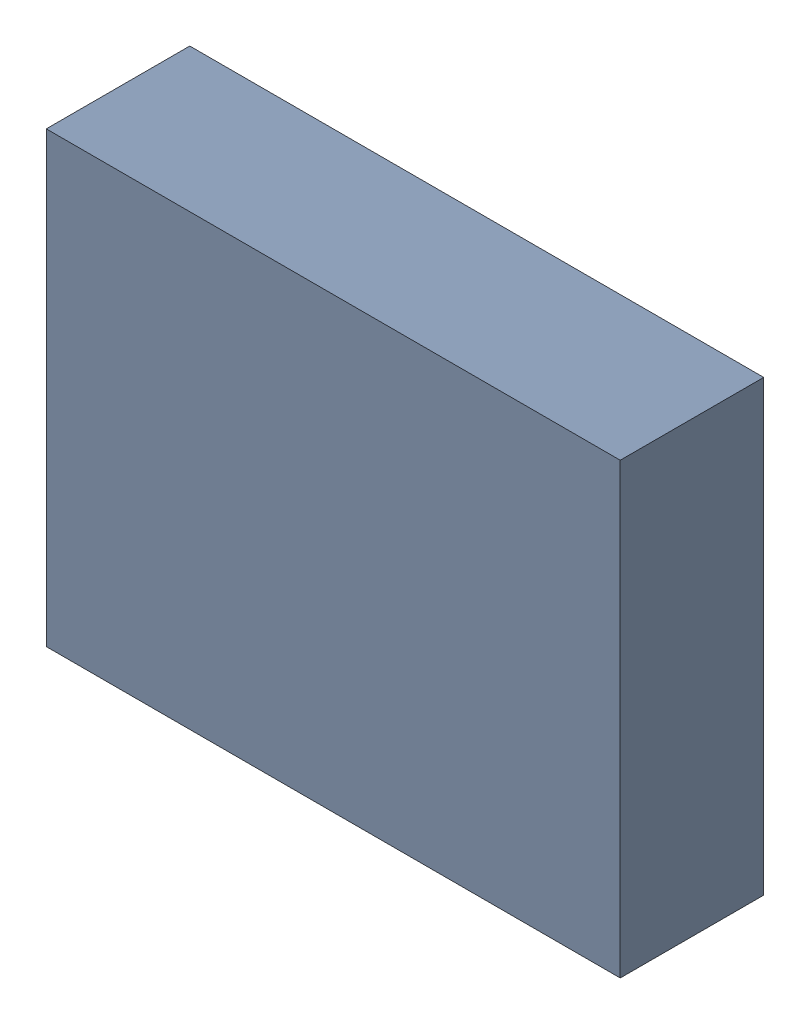
SolidWorks assembly X_TDA_TDA1, configuration Standard. Lengths in mm.
Overall size (3.2 2.5 0.8).
2 component instances, 1 part files, 0 mates.
Components (placement in the parent):
- 885545504-1: 885545504 [Standard] at (-0.42 41.94 0) size (3.2 2.5 0.8)
  - Extruded_6-1: Extruded_6 [Standard] at origin size (3.2 2.5 0.8)
